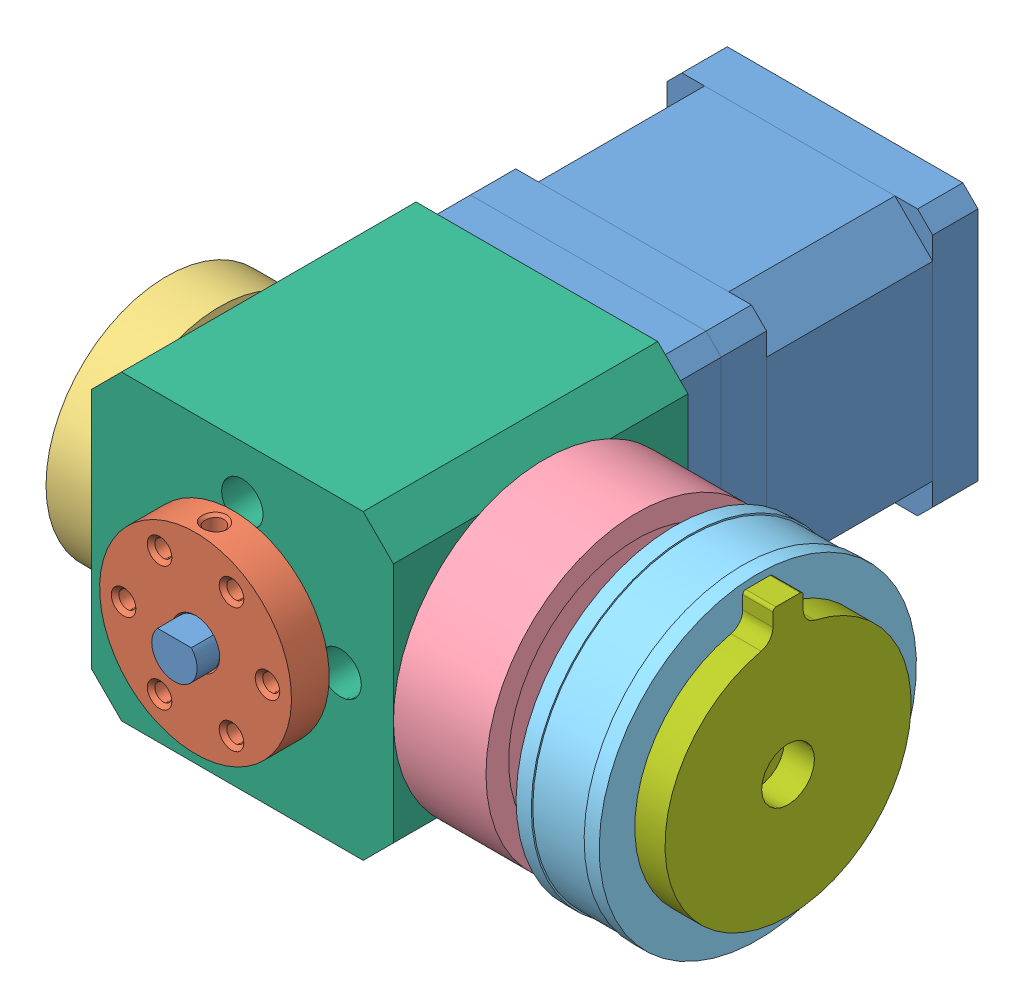
SolidWorks assembly Assemblage_Axe6, configuration Défaut. Lengths in mm.
Overall size (84.25 55.76 89.68).
7 component instances, 7 part files, 15 mates.
Components (placement in the parent):
- 14HS13-0804S-PG19-1: 14HS13-0804S-PG19 [Défaut] at (-20.2396 10.8057 -44.4) size (35.2 35.2 88.8)
- Hub_6mm_m3_2-1: Hub_6mm_m3_2 [Défaut] at (-20.2395 10.8057 39.1) x (-0.866025 0.5 0) z (0 0 -1) size (25.4 25.4 9.2)
- 61804-2RS_20x32x7-1: 61804-2RS_20x32x7 [Défaut] at (-48.2396 10.8057 17.4) x (0 0 -1) z (1 0 0) size (32 32 7)
- 30203_conique_17x40x13.25-1: 30203_conique_17x40x13.25 [Défaut] at (14.0104 10.8057 17.4) x (0 0.815939 -0.578138) z (-1 0 0) size (40 40 13.25)
- 81105TN_butée_25x42x11-1: 81105TN_butée_25x42x11 [Défaut] at (30.0104 10.8057 17.4) x (0 -0.042361 0.999102) z (-1 0 0) size (42 42 11)
- Support_Moteur_6-1: Support_Moteur_6 [Défaut] at (-20.2396 10.8057 -3.6) size (64.25 40 39)
- Butée_Moteur_6-1: Butée_Moteur_6 [Défaut] at (14.0104 10.8057 17.4) x (0 1 0) z (1 0 0) size (36.29 32.59 20)
Mates (geometry in assembly coordinates):
- Coaxiale1: concentric anti-aligned: cylinder of 14HS13-0804S-PG19-1 through (-20.2396 10.8057 44.4) axis (0 0 -1) radius 3; cylinder of Hub_6mm_m3_2-1 through (-20.2396 10.8057 41.6) axis (0 0 1) radius 3
- Coïncidente1: coincident anti-aligned: plane of 14HS13-0804S-PG19-1 through (-20.2396 10.8057 32.4) normal (0 0 1); plane of Hub_6mm_m3_2-1 through (-20.2396 10.8057 32.4) normal (0 0 -1)
- Perpendiculaire2: perpendicular: plane of 14HS13-0804S-PG19-1 through (-24.3136 12.8057 32.4) normal (0 1 0); line of Hub_6mm_m3_2-1 through (-20.2396 12.3505 39.1) axis (0 1 0)
- Coaxiale2: concentric aligned: cylinder of 14HS13-0804S-PG19-1 through (-20.2396 23.8057 18.4) axis (0 0 1) radius 1.5; cylinder of Support_Moteur_6-1 through (-20.2396 23.8057 26.4) axis (0 0 1) radius 1.5
- Coaxiale3: concentric aligned: cylinder of 14HS13-0804S-PG19-1 through (-33.2396 10.8057 18.4) axis (0 0 1) radius 1.5; cylinder of Support_Moteur_6-1 through (-33.2396 10.8057 26.4) axis (0 0 1) radius 1.5
- Coïncidente2: coincident anti-aligned: plane of 14HS13-0804S-PG19-1 through (-20.2396 10.8057 26.4) normal (0 0 1); plane of Support_Moteur_6-1 through (-20.2396 10.8057 26.4) normal (0 0 -1)
- Coaxiale4: concentric anti-aligned: cylinder of 61804-2RS_20x32x7-1 through (-41.2396 10.8057 17.4) axis (-1 0 0) radius 10; cylinder of Support_Moteur_6-1 through (-50.2396 10.8057 17.4) axis (1 0 0) radius 10
- Coïncidente3: coincident anti-aligned: plane of 61804-2RS_20x32x7-1 through (-41.2396 10.8057 17.4) normal (1 0 0); plane of Support_Moteur_6-1 through (-41.2396 10.8057 17.4) normal (-1 0 0)
- Coaxiale5: concentric anti-aligned: cylinder of 30203_conique_17x40x13.25-1 through (0.7604 10.8057 17.4) axis (1 0 0) radius 8.5; cylinder of Support_Moteur_6-1 through (14.0104 10.8057 17.4) axis (-1 0 0) radius 8.5
- Coïncidente4: coincident anti-aligned: plane of 30203_conique_17x40x13.25-1 through (0.7604 10.8057 17.4) normal (-1 0 0); plane of Support_Moteur_6-1 through (0.7604 10.8057 17.4) normal (1 0 0)
- Coaxiale6: concentric anti-aligned: cylinder of Support_Moteur_6-1 through (-50.2396 10.8057 17.4) axis (1 0 0) radius 2; cylinder of Butée_Moteur_6-1 through (30.0104 10.8057 17.4) axis (-1 0 0) radius 2
- Coïncidente5: coincident anti-aligned: plane of Support_Moteur_6-1 through (14.0104 10.8057 17.4) normal (1 0 0); plane of Butée_Moteur_6-1 through (14.0104 10.8057 17.4) normal (-1 0 0)
- Coaxiale7: concentric anti-aligned: cylinder of 81105TN_butée_25x42x11-1 through (19.0104 10.8057 17.4) axis (1 0 0) radius 12.5; cylinder of Butée_Moteur_6-1 through (30.0104 10.8057 17.4) axis (-1 0 0) radius 12.5
- Coïncidente6: coincident anti-aligned: plane of 81105TN_butée_25x42x11-1 through (30.0104 10.8057 17.4) normal (1 0 0); plane of Butée_Moteur_6-1 through (30.0104 10.8057 17.4) normal (-1 0 0)
- Coaxiale8: concentric anti-aligned: circle of Butée_Moteur_6-1; circle of Support_Moteur_6-1
